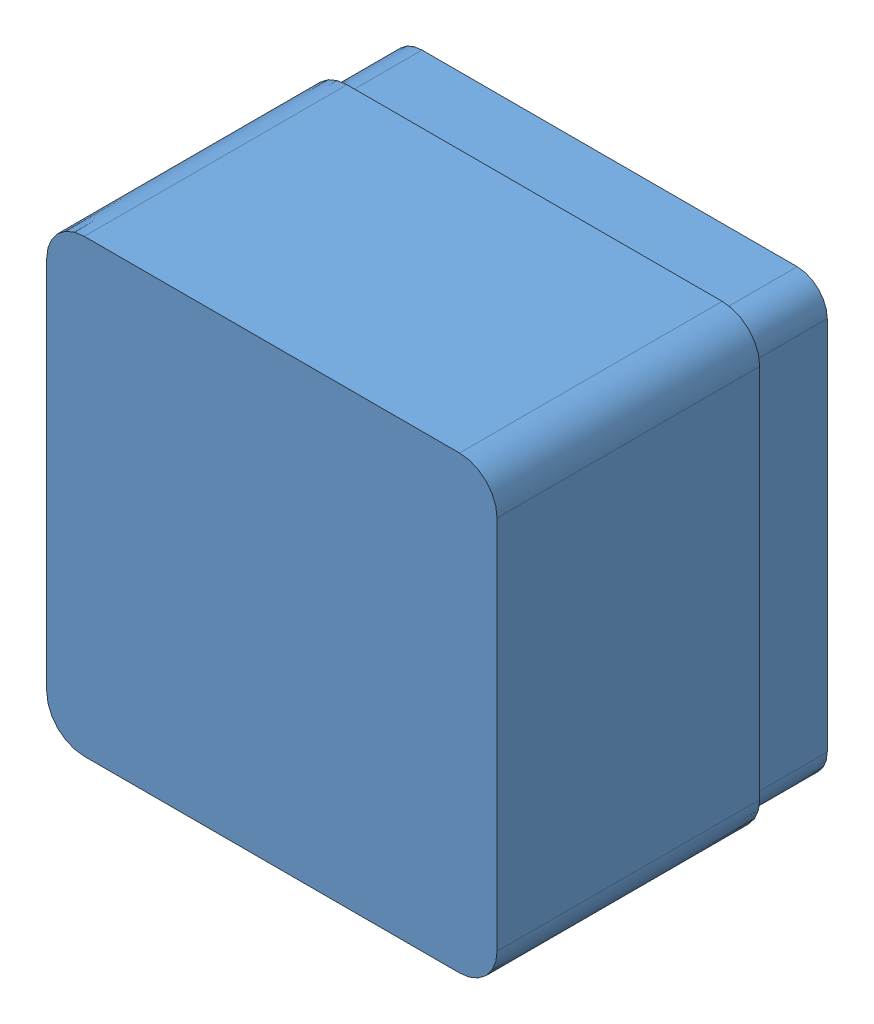
SolidWorks assembly Leg_ part_2, configuration Default. Lengths in mm.
Overall size (120 120 90).
2 component instances, 2 part files, 2 mates.
Components (placement in the parent):
- Tutor2-1: Tutor2 [Default] at origin size (120 120 90)
- jkjkbjknv-1: jkjkbjknv [Default] at (0 0 20) x (1 0 0) z (0 0 -1) (suppressed, hidden)
Mates (geometry in assembly coordinates):
- Coincident1: coincident aligned: line of Part69-1 through (120 -10 20) axis (0 -1 0); line of Tutor2-1 through (120 -10 20) axis (0 -1 0)
- Coincident2: coincident anti-aligned: plane of Tutor2-1 through (10 -2 20) normal (0 1 0); plane of Part69-1 through (0 -2 -10) normal (0 -1 0)
